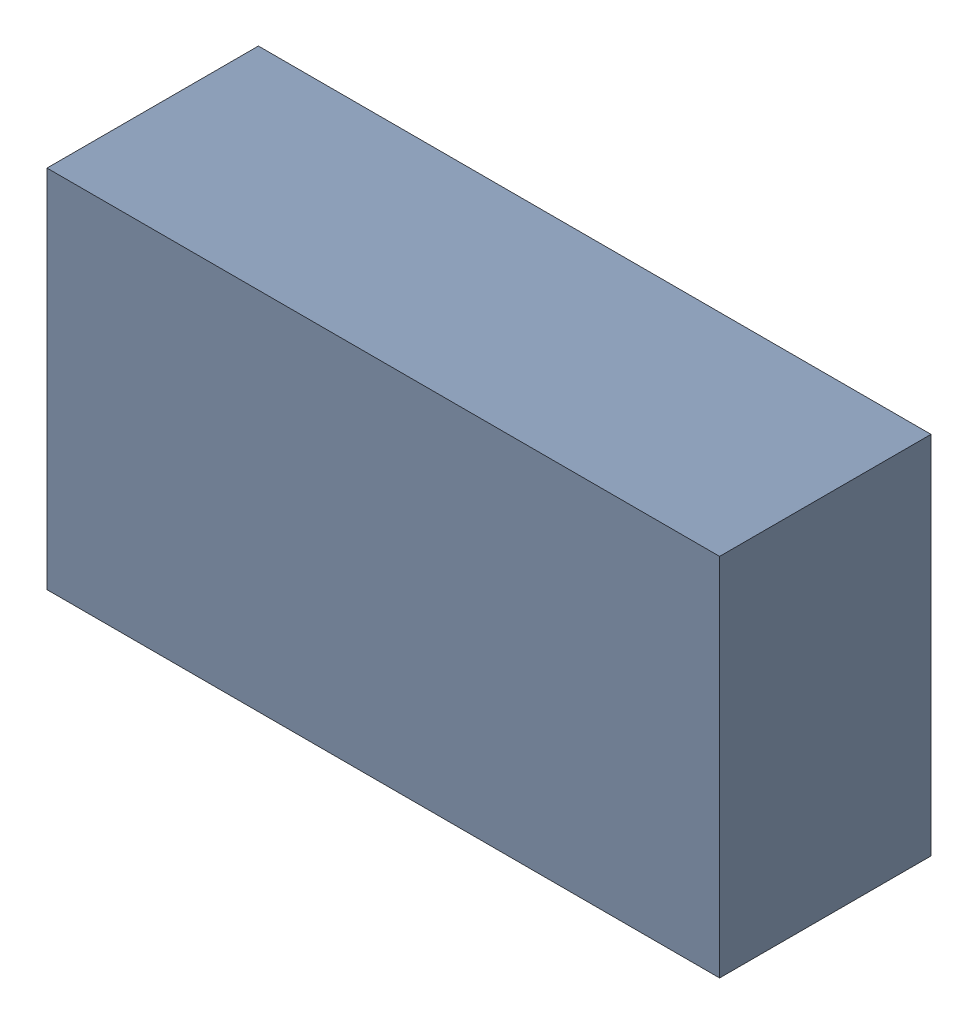
SolidWorks assembly L4_TDA1, configuration Standard. Lengths in mm.
Overall size (1.75 0.95 0.55).
2 component instances, 1 part files, 0 mates.
Components (placement in the parent):
- 885542648-1: 885542648 [Standard] at (-0.22 59.14 0) size (1.75 0.95 0.55)
  - Extruded_19-1: Extruded_19 [Standard] at origin size (1.75 0.95 0.55)
